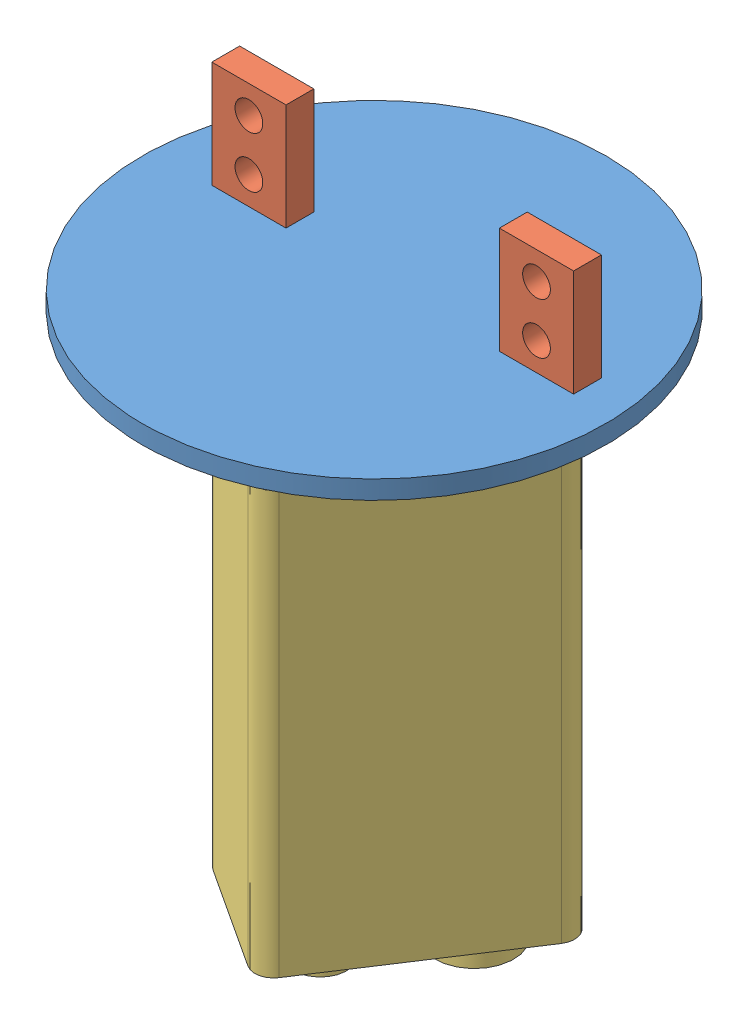
SolidWorks assembly Elektro, configuration Standard. Lengths in mm.
Overall size (74.46 63.5 55.28).
4 component instances, 3 part files, 7 mates.
Components (placement in the parent):
- E-Part-1: E-Part [Standard] at (0.3501 -2.1253 50) size (74.46 2 55.28)
- E-Befestigung-1: E-Befestigung [Standard] at (-10.1499 -0.1253 49) size (8 11.5 3)
- E-Befestigung-2: E-Befestigung [Standard] at (20.8501 -0.1253 49) size (8 11.5 3)
- 9V-1: 9V [Standard] at (-3.3779 -2.1253 64.2356) x (-0.837169 0 -0.546944) z (-0.546944 0 0.837169) size (17 50 26)
Mates (geometry in assembly coordinates):
- Deckungsgleich5: coincident anti-aligned: plane of E-Part-1 through (0.3501 -0.1253 50) normal (0 1 0); plane of E-Befestigung-1 through (-10.1499 -0.1253 49) normal (0 -1 0)
- Deckungsgleich6: coincident anti-aligned: plane of E-Part-1 through (0.3501 -0.1253 50) normal (0 1 0); plane of E-Befestigung-2 through (20.8501 -0.1253 49) normal (0 -1 0)
- Abstand2: distance = 10.5 mm: line of E-Befestigung-1 through (-10.1499 -0.1253 49) axis (0 0 -1); line of E-Part-1 through (0.3501 -0.1253 22.8782) axis (0 0 1)
- Abstand3: distance = 12.5 mm: line of E-Befestigung-2 through (12.8501 -0.1253 46) axis (0 0 1); line of E-Part-1 through (0.3501 -0.1253 22.8782) axis (0 0 1)
- Abstand6: distance = 4 mm: line of E-Befestigung-2 through (20.8501 -0.1253 46) axis (-1 0 0); line of E-Part-1 through (36.8365 -0.1253 50) axis (-1 0 0)
- Abstand7: distance = 4 mm: line of E-Befestigung-1 through (-10.1499 -0.1253 46) axis (-1 0 0); line of E-Part-1 through (36.8365 -0.1253 50) axis (-1 0 0)
- Deckungsgleich14: coincident anti-aligned: plane of E-Part-1 through (0.3501 -2.1253 50) normal (0 -1 0); plane of 9V-1 through (-3.3779 -2.1253 64.2356) normal (0 1 0)
